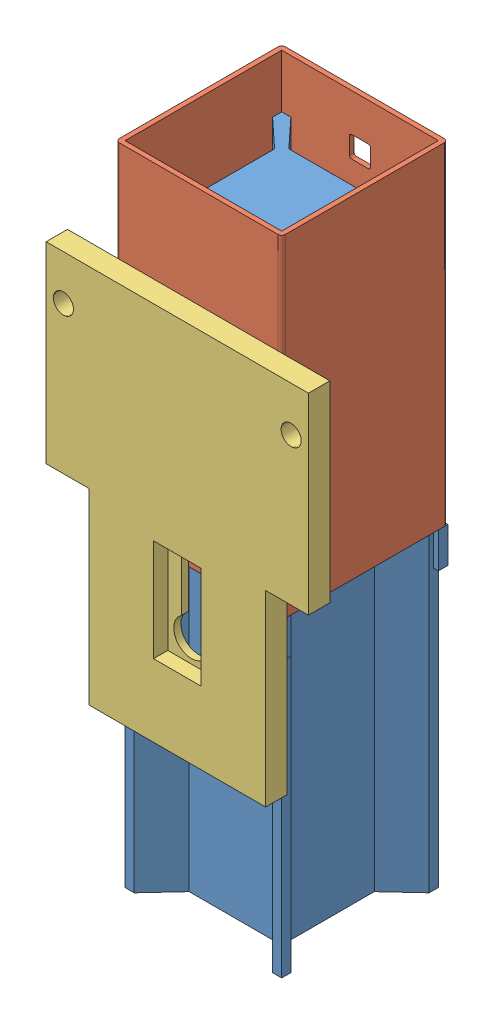
SolidWorks assembly B40-5F--1, configuration Default. Lengths in mm.
Overall size (110.5 272.5 79).
3 component instances, 3 part files, 0 mates.
Components (placement in the parent):
- B00-042-KR--1: B00-042-KR- [Default] at origin size (70 250 70)
- G2284--1: G2284- [Default] at (0 77.5 0) x (0 0 -1) z (1 0 0) size (70 140 70)
- Rail_Plate--1: Rail_Plate- [Default] at (0 -55 35) size (110.5 160 9)
